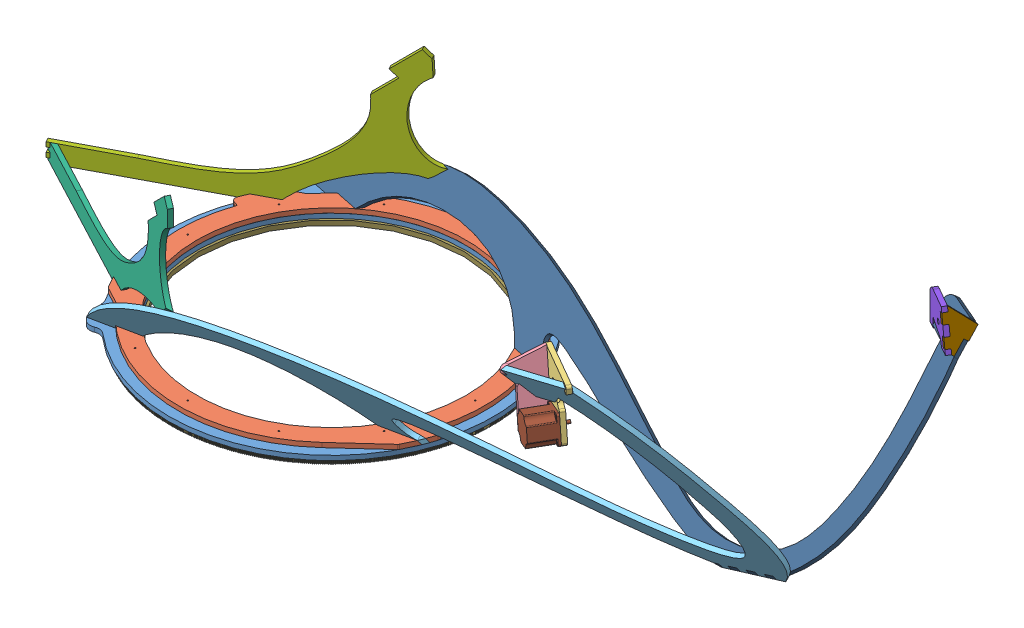
SolidWorks assembly Assem2, configuration Default. Lengths in mm.
Overall size (1767 562.96 1027.78).
12 component instances, 12 part files, 32 mates.
Components (placement in the parent):
- Circular Base-1: Circular Base [Default] at (-58.9389 49.7489 -2.6974) size (711 10 711)
- Circular Base layer 2-1: Circular Base layer 2 [Default] at (-58.9389 69.7489 -2.6974) x (1 0 0) z (0 -1 0) size (674.73 670 10)
- left axle plate-1: left axle plate [Default] at (703.853 464.7489 260.293) x (0.866025 0 0.5) z (-0.5 0 0.866025) size (124.63 145.71 10)
- Left back plate-1: Left back plate [Default] at (696.8023 369.542 256.2222) x (-0.5 0 0.866025) z (-0.845415 -0.216867 -0.488101) size (84.72 140.72 10)
- Left side-1: Left side [Default] at (-752.3786 538.9874 642.1404) x (0.984015 0.049102 -0.17118) z (0.17118 -0.525834 0.833185) size (1355.4 566.13 10)
- mirror Support-1: mirror Support [Default] at (-166.9112 217.7808 256.9185) x (0.884433 0 0.466667) z (-0.466667 0 0.884433) size (635.71 342.97 10)
- mirror Support 2-1: mirror Support 2 [Default] at (-166.9112 217.7808 340.9221) x (0.884433 0 0.466667) z (-0.466667 0 0.884433) size (383.76 342.07 545.62)
- Right axle plate-1: Right axle plate [Default] at (1012.5282 464.7489 -274.348) x (0.866025 0 0.5) z (0 -1 0) size (93.54 10 75.6)
- Right back plate-1: Right back plate [Default] at (1015.2546 501.5949 -261.2269) x (0.27314 -0.94896 0.157698) z (-0.5 0 0.866025) size (83.03 10 55.83)
- Right Side-1: Right Side [Default] at (-115.0069 141.9753 -267.9919) x (0.985842 0.055197 0.158332) z (-0.158332 0.617278 0.770648) size (1419.63 573.98 10)
- Stepper (Sparkfun 125oz)-1: Stepper (Sparkfun 125oz) [Default] at (656.3324 415.3875 306.7578) x (0.845415 0.216867 0.488101) z (-0.187812 0.976201 -0.108434) size (56.4 77.1 56.4)
- 700 teeth-1: 700 teeth [Gear Blank] at (-58.9389 49.7489 -2.6974) x (1 0 0) z (0 -1 0) size (702 702 10)
Mates (geometry in assembly coordinates):
- Coincident1: coincident anti-aligned: plane of Circular Base-1 through (-58.9389 59.7489 -2.6974) normal (0 1 0); plane of Circular Base layer 2-1 through (-58.9389 59.7489 -2.6974) normal (0 -1 0)
- Concentric1: concentric anti-aligned: circle of Circular Base-1; circle of Circular Base layer 2-1
- Coincident3: coincident anti-aligned: plane of Circular Base layer 2-1 through (535.8006 1090.8005 725.737) normal (-0.17118 0.525834 -0.833185); plane of Left side-1 through (336.889 -780.5931 -414.4568) normal (0.17118 -0.525834 0.833185)
- Coincident4: coincident aligned: plane of Circular Base-1 through (-58.9389 49.7489 -2.6974) normal (0 -1 0); plane of Left side-1 through (-58.9389 49.7489 -2.6974) normal (0 -1 0)
- Coincident5: coincident anti-aligned: plane of Circular Base-1 through (-312.0934 55.0072 234.2343) normal (-0.97954 0 0.201249); plane of Left side-1 through (-415.3981 -775.3347 -268.581) normal (0.97954 0 -0.201249)
- Coincident6: coincident anti-aligned: plane of Circular Base layer 2-1 through (-771.4223 59.7489 -62.0487) normal (-0.466667 0 0.884433); plane of mirror Support-1 through (-337.5693 126.376 166.8717) normal (0.466667 0 -0.884433)
- Coincident7: coincident anti-aligned: plane of Circular Base layer 2-1 through (-391.4538 59.7489 222.3954) normal (-0.884433 0 -0.466667); plane of mirror Support-1 through (-361.469 69.7489 165.5678) normal (0.884433 0 0.466667)
- Coincident8: coincident anti-aligned: plane of Circular Base-1 through (-58.9389 59.7489 -2.6974) normal (0 1 0); plane of mirror Support-1 through (-680.3675 59.7489 -2.6974) normal (0 -1 0)
- Coincident9: coincident anti-aligned: plane of Left side-1 through (335.1772 -775.3347 -422.7886) normal (-0.17118 0.525834 -0.833185); plane of mirror Support-1 through (-72.7976 234.9367 298.6263) normal (0.17118 -0.525834 0.833185)
- Coincident10: coincident anti-aligned: plane of Circular Base-1 through (-58.9389 59.7489 -2.6974) normal (0 1 0); plane of mirror Support 2-1 through (-680.3675 59.7489 -2.6974) normal (0 -1 0)
- Coincident11: coincident anti-aligned: plane of Circular Base layer 2-1 through (-776.6399 59.7489 59.4069) normal (-0.466667 0 -0.884433); plane of mirror Support 2-1 through (-337.5693 126.376 -172.2664) normal (0.466667 0 0.884433)
- Coincident12: coincident anti-aligned: plane of Circular Base layer 2-1 through (-386.2363 59.7489 -217.9018) normal (-0.884433 0 0.466667); plane of mirror Support 2-1 through (-361.469 69.7489 -170.9625) normal (0.884433 0 -0.466667)
- Coincident13: coincident anti-aligned: plane of Circular Base-1 through (-58.9389 59.7489 -2.6974) normal (0 1 0); plane of Right Side-1 through (93.0592 59.7489 -93.4617) normal (0 -1 0)
- Coincident14: coincident anti-aligned: plane of Circular Base layer 2-1 through (-690.3717 190.9493 -438.4056) normal (-0.158332 0.617278 0.770648); plane of Right Side-1 through (477.3715 112.9947 -136.0493) normal (0.158332 -0.617278 -0.770648)
- Coincident15: coincident anti-aligned: plane of Circular Base-1 through (-438.2264 -759.0054 374.2985) normal (-0.97954 0 -0.201249); plane of Right Side-1 through (-311.4991 43.5761 -242.5214) normal (0.97954 0 0.201249)
- Coincident16: coincident anti-aligned: plane of left axle plate-1 through (739.9746 489.7489 292.6948) normal (0 -1 0); plane of Left side-1 through (739.9746 489.7489 292.6948) normal (0 1 0)
- Coincident17: coincident anti-aligned: plane of Left back plate-1 through (160.9445 195.9764 226.015) normal (0.17118 -0.525834 0.833185); plane of Left side-1 through (335.1772 -775.3347 -422.7886) normal (-0.17118 0.525834 -0.833185)
- Coincident18: coincident anti-aligned: plane of Left back plate-1 through (652.3586 473.5036 266.5224) normal (-0.48633 0.690363 0.535614); plane of Left side-1 through (528.1839 424.961 216.341) normal (0.48633 -0.690363 -0.535614)
- Coincident19: coincident aligned: plane of Left back plate-1 through (661.9183 504.7489 236.082) normal (-0.845415 -0.216867 -0.488101); plane of Left side-1 through (706.8501 507.2454 157.1486) normal (-0.845415 -0.216867 -0.488101)
- Coincident20: coincident anti-aligned: plane of left axle plate-1 through (664.4308 465.7008 249.0796) normal (-0.187812 0.976201 -0.108434); plane of Left back plate-1 through (648.0989 467.8695 296.8913) normal (0.187812 -0.976201 0.108434)
- Coincident21: coincident anti-aligned: plane of left axle plate-1 through (724.5114 504.7489 283.7671) normal (-0.5 0 0.866025); plane of Left back plate-1 through (705.5499 298.0851 272.8197) normal (0.5 0 -0.866025)
- Coincident22: coincident anti-aligned: plane of Right back plate-1 through (1022.986 492.1053 -268.3102) normal (-0.821824 -0.315395 -0.47448); plane of Right Side-1 through (1051.7466 442.4932 -285.1469) normal (0.821824 0.315395 0.47448)
- Coincident23: coincident anti-aligned: plane of Right back plate-1 through (1052.1433 453.0055 -271.7461) normal (-0.055197 -0.784806 0.617278); plane of Right Side-1 through (1042.4504 451.2389 -274.8589) normal (0.055197 0.784806 -0.617278)
- Coincident24: coincident anti-aligned: plane of Right back plate-1 through (-349.3297 20.8518 -219.116) normal (0.158332 -0.617278 -0.770648); plane of Right Side-1 through (475.7882 119.1675 -128.3428) normal (-0.158332 0.617278 0.770648)
- Coincident25: coincident anti-aligned: plane of Right axle plate-1 through (1028.4488 473.1261 -265.1562) normal (-0.27314 0.94896 -0.157698); plane of Right back plate-1 through (1031.6671 476.2801 -251.7512) normal (0.27314 -0.94896 0.157698)
- Coincident26: coincident aligned: plane of Right axle plate-1 through (1014.5468 432.1708 -261.6356) normal (-0.5 0 0.866025); plane of Right back plate-1 through (1026.2042 495.2593 -254.9051) normal (-0.5 0 0.866025)
- Coincident27: coincident aligned: plane of Right axle plate-1 through (1045.2315 429.1537 -243.9197) normal (0.821824 0.315395 0.47448); plane of Right back plate-1 through (1031.2042 495.2593 -263.5654) normal (0.821824 0.315395 0.47448)
- Concentric2: concentric anti-aligned: cylinder of Stepper (Sparkfun 125oz)-1 through (724.0194 393.9743 256.8095) axis (-0.5 0 0.866025) radius 3.175; cylinder of left axle plate-1 through (712.4694 393.9743 276.8147) axis (0.5 0 -0.866025) radius 23.4798
- Coincident28: coincident anti-aligned: plane of left axle plate-1 through (724.5114 504.7489 283.7671) normal (-0.5 0 0.866025); plane of Stepper (Sparkfun 125oz)-1 through (696.9697 365.8537 267.8659) normal (0.5 0 -0.866025)
- Parallel1: parallel aligned: plane of Left back plate-1 through (670.3724 506.9175 240.963) normal (0.845415 0.216867 0.488101); plane of Stepper (Sparkfun 125oz)-1 through (740.7369 377.0809 293.1349) normal (0.845415 0.216867 0.488101)
- Coincident29: coincident anti-aligned: plane of Circular Base-1 through (-58.9389 49.7489 -2.6974) normal (0 -1 0); plane of 700 teeth-1 through (-59.5187 49.7489 347.8664) normal (0 1 0)
- Concentric3: concentric anti-aligned: cylinder of Circular Base-1 through (-58.9389 59.7489 -2.6974) axis (0 -1 0) radius 295; cylinder of 700 teeth-1 through (-58.9389 39.7489 -2.6974) axis (0 1 0) radius 291
